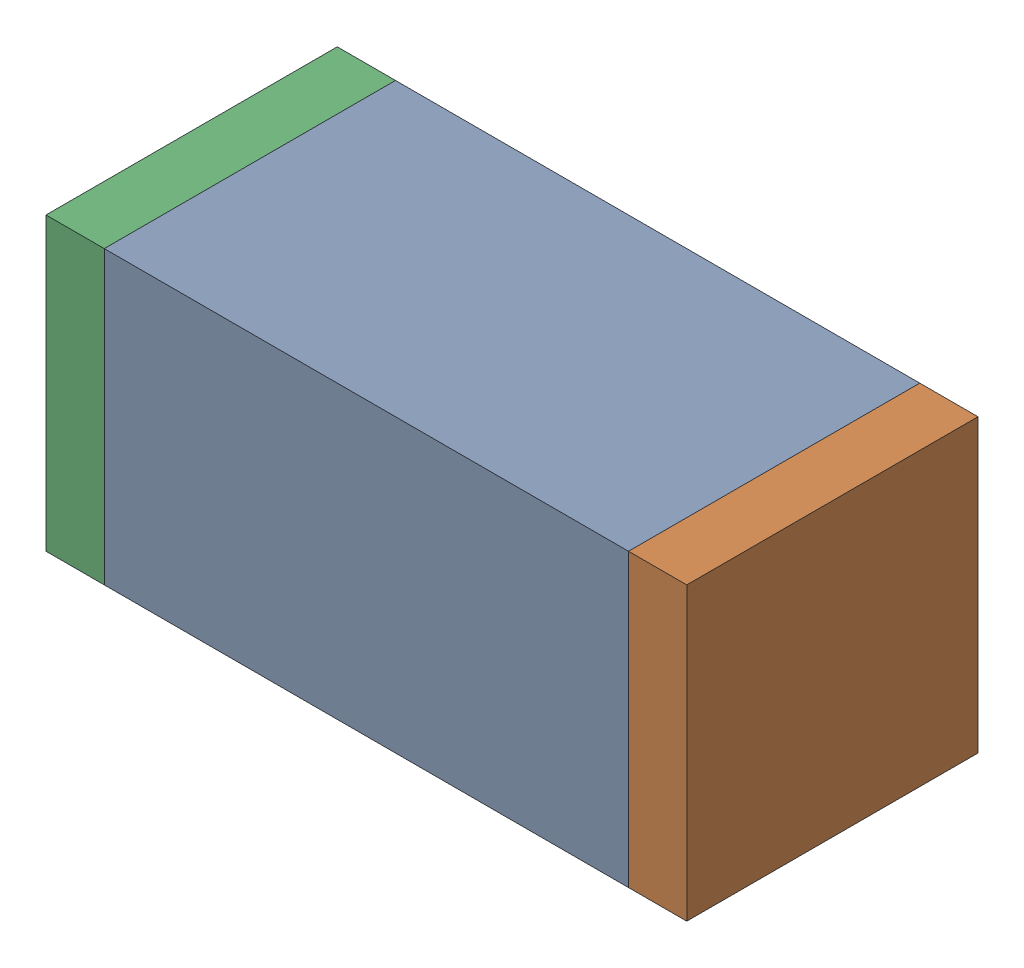
SolidWorks assembly C9, configuration Default. Lengths in mm.
Overall size (1.1 0.5 0.5).
6 component instances, 2 part files, 0 mates.
Components (placement in the parent):
- 836749680-1: 836749680 [Default] at (131.15 8.55 0) size (0.9 0.5 0.5)
  - Extruded_4-1: Extruded_4 [Default] at origin size (0.9 0.5 0.5)
- 810156080-1: 810156080 [Default] at (131.65 8.55 0) size (0.1 0.5 0.5)
  - Extruded_5-1: Extruded_5 [Default] at origin size (0.1 0.5 0.5)
- 810156080-2: 810156080 [Default] at (130.65 8.55 0) size (0.1 0.5 0.5)
  - Extruded_5-1: Extruded_5 [Default] at origin size (0.1 0.5 0.5)
